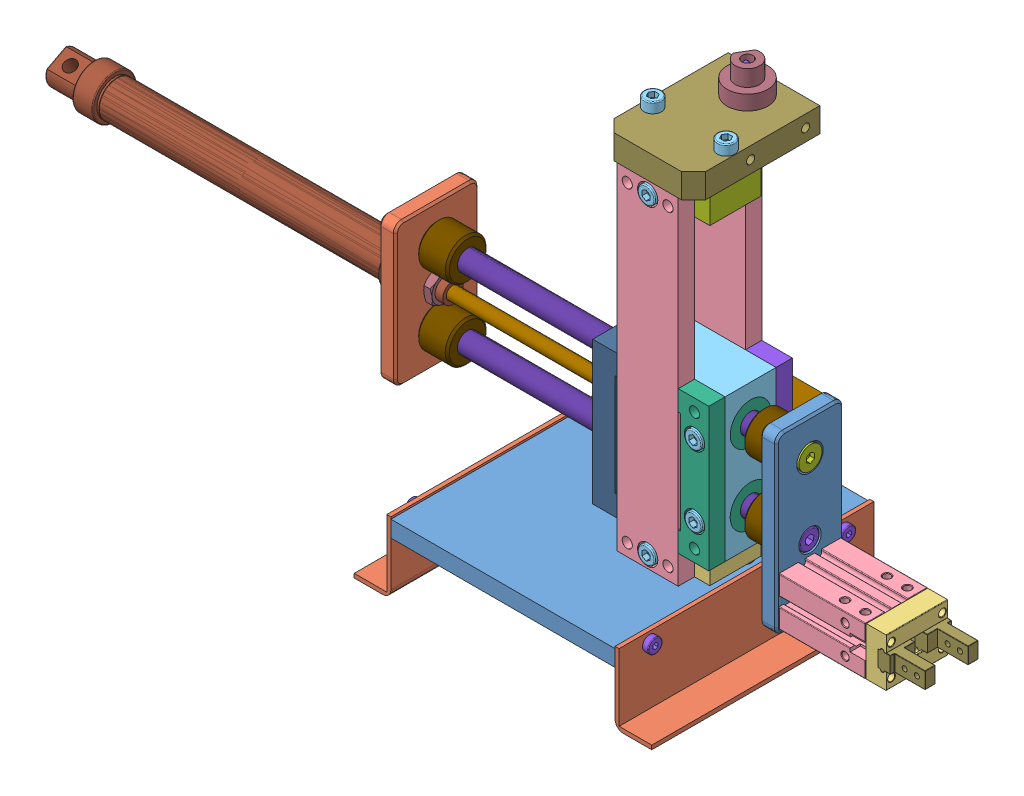
SolidWorks assembly Cum_lap_rap_S5_hoan_thien, configuration Default. Lengths in mm.
Overall size (436.7 226.2 125).
64 component instances, 31 part files, 157 mates.
Components (placement in the parent):
- tam de lon-1: tam de lon [Default] at (42.5889 56.6685 101.1963) size (110 8 125)
- khoi do-1: khoi do [Default] at (98.4472 49.4552 163.6963) x (0 0 -1) z (-1 0 0) size (125 35 18)
- khoi do-2: khoi do [Default] at (-13.2695 49.4552 38.6963) x (0 0 1) z (1 0 0) size (125 35 18)
- mieng dem duoi-1: mieng dem duoi [Default] at (71.5889 64.6685 101.1963) size (45 12 25)
- thanh dan huong lon x2-1: thanh dan huong lon x2 [Default] at (71.5889 147.1685 113.6963) x (1 0 0) z (0 -1 0) size (30 8 165)
- thanh dan huong lon x2-2: thanh dan huong lon x2 [Default] at (71.5889 147.1685 88.6963) x (1 0 0) z (0 1 0) size (30 8 165)
- con truot s4 -1: con truot s4  [Default] at (79.0889 78.6685 101.1963) x (-1 0 0) z (0 0 -1) size (45 70 25)
- bac lot-1: bac lot [Default] at (101.5889 96.1685 101.1963) x (0 1 0) z (0 0 1) size (20 12 20)
- bac lot-2: bac lot [Default] at (101.5889 131.1685 101.1963) x (0 1 0) z (0 0 1) size (20 12 20)
- bac lot-3: bac lot [Default] at (56.5889 131.1685 101.1963) x (0 0.381849 -0.924225) z (0 -0.924225 -0.381849) size (20 12 20)
- bac lot-4: bac lot [Default] at (56.5889 96.1685 101.1963) x (0 0.381849 -0.924225) z (0 -0.924225 -0.381849) size (20 12 20)
- mieng dem tren-1: mieng dem tren [Default] at (71.5889 217.6685 101.1963) size (45 12 25)
- thanh dan huong so 2 s4-3: thanh dan huong so 2 s4 [Default] at (94.0889 113.6685 88.6963) x (-1 0 0) z (0 -1 0) size (15 8 70)
- thanh ngang-5: thanh ngang [Default] at (73.0889 110.6685 65.6963) x (-1 0 0) z (0 1 0) size (57 15 25)
- tam dan huong-4: tam dan huong [Default] at (44.5889 113.6685 101.1963) x (0 -1 0) z (0 0 1) size (70 12 41)
- dai oc-1: dai oc [Default] at (71.5889 113.6685 65.6963) x (0 1 0) z (1 0 0) size (16 14 16)
- tam de nho-4: tam de nho [Default] at (71.5889 241.6685 90.6963) x (1 0 0) z (0 0 -1) size (45 12 62)
- dau kep truc vit-2: dau kep truc vit [Default] at (71.5889 256.8685 72.6963) x (-0.859142 0 -0.511737) z (-0.511737 0 0.859142) size (20 25 20)
- vong_dem-2: vong_dem [Default] at (71.5889 229.8685 72.6963) x (0.969315 0 0.245821) z (-0.245821 0 0.969315) size (19.6 2 19.6)
- vit me M8x150mm-2: vit me M8x150mm [Default] at (71.5889 171.8685 72.6963) x (0.924585 0 -0.380975) z (0 1 0) size (10.85 10.06 150.11)
- hex nut gradec_din-2: hex nut gradec_din [Hexagon Nut ISO 4034 - M8 - N] at (71.5889 221.9685 72.6963) x (-0.859606 0 0.510958) z (0 -1 0) size (13 15.01 7.9)
- chot dan huong-1: chot dan huong [Default] at (122.7513 131.1685 101.1963) x (0 0.988897 -0.148604) z (0 0.148604 0.988897) size (10 175 10)
- chot dan huong-2: chot dan huong [Default] at (122.7513 96.1685 101.1963) x (0 0.324021 0.94605) z (0 -0.94605 0.324021) size (10 175 10)
- bac chan-1: bac chan [Default] at (122.7513 131.1685 101.1963) x (0 0.942027 0.335537) z (0 -0.335537 0.942027) size (20 15 20)
- bac chan-2: bac chan [Default] at (122.7513 96.1685 101.1963) x (0 1 0) z (0 0 1) size (20 15 20)
- bac chan-3: bac chan [Default] at (-37.2487 131.1685 101.1963) x (0 0.628565 -0.777757) z (0 0.777757 0.628565) size (20 15 20)
- bac chan-4: bac chan [Default] at (-37.2487 96.1685 101.1963) x (0 0.99939 -0.03491) z (0 0.03491 0.99939) size (20 15 20)
- ban canh truoc-1: ban canh truoc [Default] at (122.7513 105.6685 101.1963) x (0 0 -1) z (0 -1 0) size (33 8 86)
- ban canh sau-1: ban canh sau [Default] at (-52.2487 113.6685 101.1963) x (0 0 -1) z (0 1 0) size (41 8 70)
- NMHZ2-16D-2: NMHZ2-16D [Default] at (115.7633 75.1106 123.6032) x (0 0 -1) z (1 0 0) size (30.6 23.6 52.5)
  - NMHZ2-16D Slipway-1: NMHZ2-16D Slipway [Default] at (22.4069 2.6078 57.488) size (30.1 23.6 10)
  - NMHZ2-16D cylinder-2: NMHZ2-16D cylinder [Default] at (22.4069 2.6078 14.988) size (30.6 23.6 42.5)
- socket head cap screw_din-2: socket head cap screw_din [DIN 912 M5 x 16 --- 16N] at (94.5889 131.1685 79.8963) x (0 0 1) z (-1 0 0) size (21 8.5 8.5)
- socket head cap screw_din-3: socket head cap screw_din [DIN 912 M5 x 16 --- 16N] at (50.0889 107.1685 66.3963) x (0 0 1) z (-1 0 0) size (21 8.5 8.5)
- socket head cap screw_din-4: socket head cap screw_din [DIN 912 M5 x 16 --- 16N] at (94.5889 120.1685 66.3963) x (0 0 1) z (-1 0 0) size (21 8.5 8.5)
- socket head cap screw_din-5: socket head cap screw_din [DIN 912 M5 x 16 --- 16N] at (94.5889 96.1685 79.8963) x (0 0 1) z (-1 0 0) size (21 8.5 8.5)
- socket head cap screw_din-6: socket head cap screw_din [DIN 912 M5 x 16 --- 16N] at (71.5889 70.6685 79.8963) x (0 0 1) z (0.989815 0.142357 0) size (21 8.5 8.5)
- socket head cap screw_din-9: socket head cap screw_din [DIN 912 M5 x 8 --- 8N] at (71.5889 70.6685 122.4963) x (0 0 -1) z (1 0 0) size (13 8.5 8.5)
- socket head cap screw_din-10: socket head cap screw_din [DIN 912 M5 x 8 --- 8N] at (45.2889 84.6685 108.6963) size (13 8.5 8.5)
- socket head cap screw_din-11: socket head cap screw_din [DIN 912 M5 x 8 --- 8N] at (45.2889 142.6685 93.6963) size (13 8.5 8.5)
- thanh dan huong s4-1: thanh dan huong s4 [Default] at (94.0889 113.6685 113.6963) x (-1 0 0) z (0 1 0) size (15 8 70)
- socket head cap screw_din-13: socket head cap screw_din [DIN 912 M5 x 12 --- 12N] at (94.5889 96.1685 122.4963) x (0 0 -1) z (1 0 0) size (17 8.5 8.5)
- socket head cap screw_din-14: socket head cap screw_din [DIN 912 M5 x 12 --- 12N] at (94.5889 131.1685 122.4963) x (0 0 -1) z (1 0 0) size (17 8.5 8.5)
- socket head cap screw_din-15: socket head cap screw_din [DIN 912 M5 x 12 --- 12N] at (53.5889 246.6685 101.1963) x (0 -1 0) z (0 0 1) size (17 8.5 8.5)
- socket head cap screw_din-16: socket head cap screw_din [DIN 912 M5 x 12 --- 12N] at (89.5889 246.6685 101.1963) x (0 -1 0) z (0 0 1) size (17 8.5 8.5)
- socket head cap screw_din-17: socket head cap screw_din [DIN 912 M5 x 12 --- 12N] at (71.5889 223.6685 79.8963) x (0 0 1) z (-1 0 0) size (17 8.5 8.5)
- socket head cap screw_din-18: socket head cap screw_din [DIN 912 M5 x 12 --- 12N] at (71.5889 223.6685 122.4963) x (0 0 -1) z (1 0 0) size (17 8.5 8.5)
- socket csink head cap screw 10642_din-2: socket csink head cap screw 10642_din [EN ISO 10642 - M6 x 8 - 8N] at (-60.4687 131.1685 101.1963) x (1 0 0) z (0 0.02259 0.999745) size (8 11.34 11.34)
- socket csink head cap screw 10642_din-3: socket csink head cap screw 10642_din [EN ISO 10642 - M6 x 8 - 8N] at (130.9713 131.1685 101.1963) x (-1 0 0) z (0 -0.022602 -0.999745) size (8 11.34 11.34)
- socket head thin cap screw_din-2: socket head thin cap screw_din [DIN 7984 - M6 x 10 --- 7N] at (130.5513 96.1685 101.1963) x (-1 0 0) z (0 0.924225 0.381849) size (14 10 10)
- socket head thin cap screw_din-4: socket head thin cap screw_din [DIN 7984 - M6 x 10 --- 7N] at (-60.0487 96.1685 101.1963) size (14 10 10)
- socket head thin cap screw_din-5: socket head thin cap screw_din [DIN 7984 - M4 x 6 --- 3.9N] at (-17.2111 60.6685 53.6963) size (8.8 7 7)
- socket head thin cap screw_din-6: socket head thin cap screw_din [DIN 7984 - M4 x 6 --- 3.9N] at (-17.2111 60.6685 148.6963) size (8.8 7 7)
- socket head thin cap screw_din-7: socket head thin cap screw_din [DIN 7984 - M4 x 6 --- 3.9N] at (102.3889 60.6685 53.6963) x (-1 0 0) z (0 0.924225 0.381849) size (8.8 7 7)
- socket head thin cap screw_din-8: socket head thin cap screw_din [DIN 7984 - M4 x 6 --- 3.9N] at (102.3889 60.6685 148.6963) x (-1 0 0) z (0 0.924225 0.381849) size (8.8 7 7)
- socket head thin cap screw_din-10: socket head thin cap screw_din [DIN 7984 - M4 x 12 --- 9.9N] at (124.3513 70.3685 112.1963) size (14.8 7 7)
- socket head thin cap screw_din-11: socket head thin cap screw_din [DIN 7984 - M4 x 12 --- 9.9N] at (124.3513 85.3685 90.1963) size (14.8 7 7)
- socket head thin cap screw_din-18: socket head thin cap screw_din [DIN 7984 - M3 x 5 --- 3.5N] at (66.0045 252.8685 69.37) x (0.859142 0 0.511737) z (0.205408 0.915906 -0.344854) size (7 5.5 5.5)
- Rod-1: Rod [Default] at (-92.4392 113.6685 101.1963) x (0 0.871767 -0.48992) z (0 -0.48992 -0.871767) size (6.2 165 6.2)
- Nut 5-1: Nut 5 [Default] at (55.0889 113.6685 101.1963) x (0 0.12782 0.991797) z (0 0.991797 -0.12782) size (11.32 3 9.8)
- 16 X 100 Cylinder bore-2: 16 X 100 Cylinder bore [Default] at (-140.4487 113.6685 101.1963) x (0 -0.886193 -0.463316) z (-1 0 0) size (21.5 21.5 192)
- NMHZ2-16D air claw-1: NMHZ2-16D air claw [Default] at (181.2513 77.7185 98.1463) x (0 0 -1) z (1 0 0) size (12 10 21)
- NMHZ2-16D air claw-2: NMHZ2-16D air claw [Default] at (181.2513 77.7185 104.2463) x (0 0 1) z (1 0 0) size (12 10 21)
- hex thin nut chamfered gradeab_din-1: hex thin nut chamfered gradeab_din [Hexagon Thin Nut ISO 4035 - M8 - N] at (-52.2487 113.6685 101.1963) x (0 -0.129819 0.991538) z (-1 0 0) size (13 15.01 4)
Mates (geometry in assembly coordinates):
- Parallel1: parallel anti-aligned: plane of tam de lon-1 through (42.5889 64.6685 101.1963) normal (0 1 0); plane of khoi do-1 through (97.5889 30.6685 38.6963) normal (0 -1 0)
- Parallel2: parallel anti-aligned: plane of tam de lon-1 through (97.5889 64.6685 38.6963) normal (1 0 0); plane of khoi do-1 through (97.5889 30.6685 38.6963) normal (-1 0 0)
- Concentric1: concentric aligned: cylinder of tam de lon-1 through (82.5889 60.6685 53.6963) axis (1 0 0) radius 2.5; cylinder of khoi do-1 through (-25.4111 60.6685 53.6963) axis (1 0 0) radius 2.5
- Coincident1: coincident anti-aligned: plane of tam de lon-1 through (97.5889 64.6685 38.6963) normal (1 0 0); plane of khoi do-1 through (97.5889 30.6685 38.6963) normal (-1 0 0)
- Parallel3: parallel anti-aligned: plane of tam de lon-1 through (42.5889 64.6685 101.1963) normal (0 1 0); plane of khoi do-2 through (-12.4111 30.6685 163.6963) normal (0 -1 0)
- Parallel4: parallel anti-aligned: plane of tam de lon-1 through (-12.4111 64.6685 38.6963) normal (-1 0 0); plane of khoi do-2 through (-12.4111 30.6685 163.6963) normal (1 0 0)
- Concentric2: concentric aligned: cylinder of tam de lon-1 through (2.5889 60.6685 148.6963) axis (-1 0 0) radius 2.5; cylinder of khoi do-2 through (110.5889 60.6685 148.6963) axis (-1 0 0) radius 2.5
- Coincident2: coincident anti-aligned: plane of tam de lon-1 through (-12.4111 64.6685 38.6963) normal (-1 0 0); plane of khoi do-2 through (-12.4111 30.6685 163.6963) normal (1 0 0)
- Concentric3: concentric aligned: cylinder of tam de lon-1 through (89.5889 56.6685 93.6963) axis (0 1 0) radius 2.75; cylinder of mieng dem duoi-1 through (89.5889 64.6685 93.6963) axis (0 1 0) radius 2.5
- Concentric4: concentric aligned: cylinder of tam de lon-1 through (53.5889 56.6685 108.6963) axis (0 1 0) radius 2.75; cylinder of mieng dem duoi-1 through (53.5889 64.6685 108.6963) axis (0 1 0) radius 2.5
- Coincident3: coincident anti-aligned: plane of tam de lon-1 through (42.5889 64.6685 101.1963) normal (0 1 0); plane of mieng dem duoi-1 through (71.5889 64.6685 101.1963) normal (0 -1 0)
- Parallel6: parallel anti-aligned: plane of mieng dem duoi-1 through (71.5889 76.6685 101.1963) normal (0 1 0); plane of thanh dan huong lon x2-1 through (56.5889 64.6685 121.6963) normal (0 -1 0)
- Parallel7: parallel anti-aligned: plane of mieng dem duoi-1 through (49.0889 76.6685 113.6963) normal (0 0 1); plane of thanh dan huong lon x2-1 through (71.5889 147.1685 113.6963) normal (0 0 -1)
- Concentric5: concentric anti-aligned: cylinder of mieng dem duoi-1 through (81.5889 70.6685 160.6963) axis (0 0 -1) radius 2.5; cylinder of thanh dan huong lon x2-1 through (81.5889 70.6685 80.4963) axis (0 0 1) radius 2.5
- Coincident4: coincident anti-aligned: plane of mieng dem duoi-1 through (49.0889 76.6685 113.6963) normal (0 0 1); plane of thanh dan huong lon x2-1 through (71.5889 147.1685 113.6963) normal (0 0 -1)
- Parallel8: parallel anti-aligned: plane of mieng dem duoi-1 through (71.5889 76.6685 101.1963) normal (0 1 0); plane of thanh dan huong lon x2-2 through (56.5889 64.6685 80.6963) normal (0 -1 0)
- Parallel9: parallel anti-aligned: plane of mieng dem duoi-1 through (49.0889 76.6685 88.6963) normal (0 0 -1); plane of thanh dan huong lon x2-2 through (71.5889 147.1685 88.6963) normal (0 0 1)
- Concentric6: concentric aligned: cylinder of mieng dem duoi-1 through (81.5889 70.6685 160.6963) axis (0 0 -1) radius 2.5; cylinder of thanh dan huong lon x2-2 through (81.5889 70.6685 121.8963) axis (0 0 -1) radius 2.5
- Coincident5: coincident anti-aligned: plane of mieng dem duoi-1 through (49.0889 76.6685 88.6963) normal (0 0 -1); plane of thanh dan huong lon x2-2 through (71.5889 147.1685 88.6963) normal (0 0 1)
- Parallel10: parallel anti-aligned: plane of mieng dem duoi-1 through (94.0889 76.6685 88.6963) normal (1 0 0); plane of con truot s4 -1 through (56.5889 148.6685 113.6963) normal (-1 0 0)
- Parallel11: parallel aligned: plane of mieng dem duoi-1 through (71.5889 76.6685 101.1963) normal (0 1 0); plane of con truot s4 -1 through (79.0889 148.6685 101.1963) normal (0 1 0)
- Coincident6: coincident anti-aligned: plane of thanh dan huong lon x2-2 through (71.5889 147.1685 88.6963) normal (0 0 1); plane of con truot s4 -1 through (101.5889 148.6685 88.6963) normal (0 0 -1)
- Concentric7: concentric anti-aligned: cylinder of con truot s4 -1 through (126.5889 96.1685 101.1963) axis (-1 0 0) radius 6; cylinder of bac lot-1 through (89.5889 96.1685 101.1963) axis (1 0 0) radius 6
- Coincident14: coincident anti-aligned: plane of con truot s4 -1 through (99.5889 96.1685 101.1963) normal (1 0 0); plane of bac lot-1 through (99.5889 96.1685 101.1963) normal (-1 0 0)
- Concentric8: concentric anti-aligned: cylinder of con truot s4 -1 through (126.5889 131.1685 101.1963) axis (-1 0 0) radius 6; cylinder of bac lot-2 through (89.5889 131.1685 101.1963) axis (1 0 0) radius 6
- Coincident15: coincident anti-aligned: plane of con truot s4 -1 through (99.5889 131.1685 101.1963) normal (1 0 0); plane of bac lot-2 through (99.5889 131.1685 101.1963) normal (-1 0 0)
- Concentric9: concentric aligned: cylinder of con truot s4 -1 through (126.5889 131.1685 101.1963) axis (-1 0 0) radius 6; cylinder of bac lot-3 through (68.5889 131.1685 101.1963) axis (-1 0 0) radius 6
- Coincident16: coincident anti-aligned: plane of con truot s4 -1 through (58.5889 131.1685 101.1963) normal (-1 0 0); plane of bac lot-3 through (58.5889 131.1685 101.1963) normal (1 0 0)
- Concentric10: concentric aligned: cylinder of con truot s4 -1 through (126.5889 96.1685 101.1963) axis (-1 0 0) radius 6; cylinder of bac lot-4 through (68.5889 96.1685 101.1963) axis (-1 0 0) radius 6
- Coincident18: coincident anti-aligned: plane of con truot s4 -1 through (58.5889 96.1685 101.1963) normal (-1 0 0); plane of bac lot-4 through (58.5889 96.1685 101.1963) normal (1 0 0)
- Parallel23: parallel aligned: plane of thanh dan huong lon x2-2 through (56.5889 229.6685 80.6963) normal (0 1 0); plane of mieng dem tren-1 through (71.5889 229.6685 101.1963) normal (0 1 0)
- Concentric12: concentric aligned: cylinder of thanh dan huong lon x2-2 through (61.5889 223.6685 121.8963) axis (0 0 -1) radius 2.5; cylinder of mieng dem tren-1 through (61.5889 223.6685 160.6963) axis (0 0 -1) radius 2.5
- Coincident21: coincident anti-aligned: plane of thanh dan huong lon x2-2 through (71.5889 147.1685 88.6963) normal (0 0 1); plane of mieng dem tren-1 through (49.0889 229.6685 88.6963) normal (0 0 -1)
- Parallel38: parallel aligned: plane of con truot s4 -1 through (79.0889 148.6685 101.1963) normal (0 1 0); plane of thanh dan huong so 2 s4-3 through (101.5889 148.6685 80.6963) normal (0 1 0)
- Parallel39: parallel anti-aligned: plane of con truot s4 -1 through (101.5889 148.6685 88.6963) normal (0 0 -1); plane of thanh dan huong so 2 s4-3 through (94.0889 113.6685 88.6963) normal (0 0 1)
- Coincident32: coincident aligned: plane of con truot s4 -1 through (79.0889 148.6685 101.1963) normal (0 1 0); plane of thanh dan huong so 2 s4-3 through (101.5889 148.6685 80.6963) normal (0 1 0)
- Coincident33: coincident aligned: plane of con truot s4 -1 through (101.5889 148.6685 113.6963) normal (1 0 0); plane of thanh dan huong so 2 s4-3 through (101.5889 148.6685 80.6963) normal (1 0 0)
- Coincident34: coincident anti-aligned: plane of con truot s4 -1 through (101.5889 148.6685 88.6963) normal (0 0 -1); plane of thanh dan huong so 2 s4-3 through (94.0889 113.6685 88.6963) normal (0 0 1)
- Coincident36: coincident anti-aligned: plane of thanh dan huong lon x2-2 through (86.5889 64.6685 80.6963) normal (1 0 0); plane of thanh dan huong so 2 s4-3 through (86.5889 148.6685 80.6963) normal (-1 0 0)
- Parallel42: parallel anti-aligned: plane of thanh dan huong so 2 s4-3 through (101.5889 148.6685 80.6963) normal (0 1 0); plane of thanh ngang-5 through (101.5889 101.1685 80.6963) normal (0 -1 0)
- Concentric26: concentric aligned: cylinder of thanh dan huong so 2 s4-3 through (94.5889 120.1685 152.8963) axis (0 0 -1) radius 2.5; cylinder of thanh ngang-5 through (94.5889 120.1685 124.3963) axis (0 0 -1) radius 2.75
- Parallel46: parallel aligned: plane of con truot s4 -1 through (79.0889 148.6685 101.1963) normal (0 1 0); plane of tam dan huong-4 through (56.5889 148.6685 80.6963) normal (0 1 0)
- Parallel47: parallel anti-aligned: plane of con truot s4 -1 through (56.5889 148.6685 113.6963) normal (-1 0 0); plane of tam dan huong-4 through (55.5889 138.6685 33.6963) normal (1 0 0)
- Coincident40: coincident anti-aligned: plane of con truot s4 -1 through (56.5889 148.6685 113.6963) normal (-1 0 0); plane of tam dan huong-4 through (56.5889 113.6685 101.1963) normal (1 0 0)
- Concentric29: concentric aligned: cylinder of con truot s4 -1 through (71.5889 142.6685 93.6963) axis (-1 0 0) radius 2.5; cylinder of tam dan huong-4 through (132.5889 142.6685 93.6963) axis (-1 0 0) radius 2.75
- Coincident41: coincident anti-aligned: plane of thanh dan huong so 2 s4-3 through (94.0889 113.6685 80.6963) normal (0 0 -1); plane of thanh ngang-5 through (73.0889 110.6685 80.6963) normal (0 0 1)
- Parallel48: parallel anti-aligned: plane of thanh ngang-5 through (73.0889 110.6685 65.6963) normal (0 0 -1); plane of dai oc-1 through (80.1238 134.6685 79.6963) normal (0 0 1)
- Concentric30: concentric anti-aligned: cylinder of thanh ngang-5 through (71.5889 -44.8315 72.6963) axis (0 1 0) radius 5; cylinder of dai oc-1 through (71.5889 134.6685 72.6963) axis (0 -1 0) radius 4
- Concentric31: concentric aligned: cylinder of thanh ngang-5 through (71.5889 113.6685 236.6963) axis (0 0 -1) radius 8; cylinder of dai oc-1 through (71.5889 113.6685 79.6963) axis (0 0 -1) radius 8
- Parallel53: parallel anti-aligned: plane of mieng dem tren-1 through (71.5889 229.6685 101.1963) normal (0 1 0); plane of tam de nho-4 through (71.5889 229.6685 90.6963) normal (0 -1 0)
- Parallel54: parallel anti-aligned: plane of mieng dem tren-1 through (94.0889 229.6685 88.6963) normal (1 0 0); plane of tam de nho-4 through (49.0889 229.6685 121.6963) normal (-1 0 0)
- Concentric32: concentric anti-aligned: cylinder of mieng dem tren-1 through (53.5889 157.6685 101.1963) axis (0 1 0) radius 2.5; cylinder of tam de nho-4 through (53.5889 241.6685 101.1963) axis (0 -1 0) radius 2.75
- Coincident45: coincident anti-aligned: plane of mieng dem tren-1 through (71.5889 229.6685 101.1963) normal (0 1 0); plane of tam de nho-4 through (71.5889 229.6685 90.6963) normal (0 -1 0)
- Parallel55: parallel anti-aligned: plane of tam de nho-4 through (71.5889 241.6685 90.6963) normal (0 1 0); plane of dau kep truc vit-2 through (71.5889 231.8685 72.6963) normal (0 -1 0)
- Concentric33: concentric aligned: cylinder of tam de nho-4 through (71.5889 241.6685 72.6963) axis (0 -1 0) radius 7; cylinder of dau kep truc vit-2 through (71.5889 241.6685 72.6963) axis (0 -1 0) radius 7
- Coincident46: coincident anti-aligned: plane of tam de nho-4 through (71.5889 241.6685 90.6963) normal (0 1 0); plane of dau kep truc vit-2 through (71.5889 241.6685 72.6963) normal (0 -1 0)
- Concentric34: concentric aligned: cylinder of dau kep truc vit-2 through (71.5889 246.8685 72.6963) axis (0 -1 0) radius 4; cylinder of vong_dem-2 through (71.5889 231.8685 72.6963) axis (0 -1 0) radius 4.25
- Coincident47: coincident anti-aligned: plane of dau kep truc vit-2 through (71.5889 231.8685 72.6963) normal (0 -1 0); plane of vong_dem-2 through (71.5889 231.8685 72.6963) normal (0 1 0)
- Concentric35: concentric anti-aligned: cylinder of dau kep truc vit-2 through (71.5889 246.8685 72.6963) axis (0 -1 0) radius 4; cylinder of vit me M8x150mm-2 through (71.5889 171.8685 72.6963) axis (0 1 0) radius 3.933
- Coincident48: coincident anti-aligned: plane of dau kep truc vit-2 through (71.5889 246.8685 72.6963) normal (0 -1 0); plane of vit me M8x150mm-2 through (71.5889 246.8685 72.6963) normal (0 1 0)
- Concentric37: concentric anti-aligned: cylinder of vit me M8x150mm-2 through (71.5889 171.8685 72.6963) axis (0 1 0) radius 3.933; cylinder of hex nut gradec_din-2 through (71.5889 229.8685 72.6963) axis (0 -1 0) radius 3.4
- Coincident49: coincident anti-aligned: plane of vong_dem-2 through (71.5889 229.8685 72.6963) normal (0 -1 0); plane of hex nut gradec_din-2 through (67.7539 229.8685 66.2445) normal (0 1 0)
- Lock1: lock: unknown of vit me M8x150mm-2; unknown of hex nut gradec_din-2
- Lock2: lock: unknown of dau kep truc vit-2; unknown of hex nut gradec_din-2
- Concentric41: concentric anti-aligned: cylinder of bac lot-2 through (116.5889 131.1685 101.1963) axis (-1 0 0) radius 5; cylinder of chot dan huong-1 through (-150.2487 131.1685 101.1963) axis (1 0 0) radius 5
- Concentric42: concentric anti-aligned: cylinder of bac lot-1 through (116.5889 96.1685 101.1963) axis (-1 0 0) radius 5; cylinder of chot dan huong-2 through (-150.2487 96.1685 101.1963) axis (1 0 0) radius 5
- Concentric43: concentric anti-aligned: cylinder of chot dan huong-1 through (-150.2487 131.1685 101.1963) axis (1 0 0) radius 5; cylinder of bac chan-1 through (122.7513 131.1685 101.1963) axis (-1 0 0) radius 5
- Coincident53: coincident aligned: plane of chot dan huong-1 through (122.7513 131.1685 101.1963) normal (1 0 0); plane of bac chan-1 through (122.7513 131.1685 101.1963) normal (1 0 0)
- Concentric44: concentric anti-aligned: cylinder of chot dan huong-2 through (-150.2487 96.1685 101.1963) axis (1 0 0) radius 5; cylinder of bac chan-2 through (122.7513 96.1685 101.1963) axis (-1 0 0) radius 5
- Coincident54: coincident aligned: plane of chot dan huong-2 through (122.7513 96.1685 101.1963) normal (1 0 0); plane of bac chan-2 through (122.7513 96.1685 101.1963) normal (1 0 0)
- Concentric45: concentric anti-aligned: cylinder of chot dan huong-1 through (-150.2487 131.1685 101.1963) axis (1 0 0) radius 5; cylinder of bac chan-3 through (-37.2487 131.1685 101.1963) axis (-1 0 0) radius 5
- Coincident55: coincident aligned: plane of chot dan huong-1 through (-52.2487 131.1685 101.1963) normal (-1 0 0); plane of bac chan-3 through (-52.2487 131.1685 101.1963) normal (-1 0 0)
- Coincident57: coincident aligned: plane of chot dan huong-2 through (-52.2487 96.1685 101.1963) normal (-1 0 0); plane of bac chan-4 through (-52.2487 96.1685 101.1963) normal (-1 0 0)
- Concentric47: concentric aligned: cylinder of chot dan huong-1 through (102.7513 131.1685 101.1963) axis (1 0 0) radius 3; cylinder of ban canh truoc-1 through (122.7513 131.1685 101.1963) axis (1 0 0) radius 3.3
- Concentric48: concentric aligned: cylinder of chot dan huong-2 through (102.7513 96.1685 101.1963) axis (1 0 0) radius 3; cylinder of ban canh truoc-1 through (122.7513 96.1685 101.1963) axis (1 0 0) radius 3.3
- Coincident58: coincident anti-aligned: plane of chot dan huong-1 through (122.7513 131.1685 101.1963) normal (1 0 0); plane of ban canh truoc-1 through (122.7513 105.6685 101.1963) normal (-1 0 0)
- Coincident59: coincident anti-aligned: plane of chot dan huong-2 through (122.7513 96.1685 101.1963) normal (1 0 0); plane of ban canh truoc-1 through (122.7513 105.6685 101.1963) normal (-1 0 0)
- Concentric49: concentric aligned: cylinder of chot dan huong-1 through (-32.2487 131.1685 101.1963) axis (-1 0 0) radius 3; cylinder of ban canh sau-1 through (-52.2487 131.1685 101.1963) axis (-1 0 0) radius 3.3
- Concentric50: concentric aligned: cylinder of chot dan huong-2 through (-32.2487 96.1685 101.1963) axis (-1 0 0) radius 3; cylinder of ban canh sau-1 through (-52.2487 96.1685 101.1963) axis (-1 0 0) radius 3.3
- Coincident60: coincident anti-aligned: plane of chot dan huong-1 through (-52.2487 131.1685 101.1963) normal (-1 0 0); plane of ban canh sau-1 through (-52.2487 113.6685 101.1963) normal (1 0 0)
- Coincident61: coincident anti-aligned: plane of chot dan huong-2 through (-52.2487 96.1685 101.1963) normal (-1 0 0); plane of ban canh sau-1 through (-52.2487 113.6685 101.1963) normal (1 0 0)
- Concentric55: concentric anti-aligned: cylinder of ban canh truoc-1 through (122.7513 70.3685 112.1963) axis (1 0 0) radius 2.25; cylinder of NMHZ2-16D-2/NMHZ2-16D cylinder-2 through (145.7513 70.3685 112.1963) axis (-1 0 0) radius 2
- Concentric56: concentric anti-aligned: cylinder of ban canh truoc-1 through (122.7513 85.3685 90.1963) axis (1 0 0) radius 2.25; cylinder of NMHZ2-16D-2/NMHZ2-16D cylinder-2 through (145.7513 85.3685 90.1963) axis (-1 0 0) radius 2
- Coincident62: coincident anti-aligned: plane of ban canh truoc-1 through (130.7513 105.6685 101.1963) normal (1 0 0); plane of NMHZ2-16D-2/NMHZ2-16D cylinder-2 through (130.7513 77.7185 101.1963) normal (-1 0 0)
- Concentric57: concentric anti-aligned: cylinder of chot dan huong-2 through (-150.2487 96.1685 101.1963) axis (1 0 0) radius 5; cylinder of bac chan-4 through (-37.2487 96.1685 101.1963) axis (-1 0 0) radius 5
- Concentric61: concentric aligned: cylinder of thanh dan huong so 2 s4-3 through (94.5889 131.1685 88.6963) axis (0 0 -1) radius 2.75; cylinder of socket head cap screw_din-2 through (94.5889 131.1685 48.1463) axis (0 0 -1) radius 4.25
- Coincident66: coincident anti-aligned: plane of thanh dan huong so 2 s4-3 through (94.5889 131.1685 84.8963) normal (0 0 -1); plane of socket head cap screw_din-2 through (94.5889 135.4185 84.8963) normal (0 0 1)
- Concentric62: concentric aligned: cylinder of thanh ngang-5 through (50.0889 107.1685 71.3963) axis (0 0 -1) radius 5; cylinder of socket head cap screw_din-3 through (50.0889 107.1685 34.6463) axis (0 0 -1) radius 4.25
- Coincident67: coincident anti-aligned: plane of thanh ngang-5 through (50.0889 107.1685 71.3963) normal (0 0 -1); plane of socket head cap screw_din-3 through (50.0889 111.4185 71.3963) normal (0 0 1)
- Concentric63: concentric aligned: cylinder of thanh ngang-5 through (94.5889 120.1685 124.3963) axis (0 0 -1) radius 2.75; cylinder of socket head cap screw_din-4 through (94.5889 120.1685 34.6463) axis (0 0 -1) radius 4.25
- Coincident68: coincident anti-aligned: plane of thanh ngang-5 through (94.5889 120.1685 71.3963) normal (0 0 -1); plane of socket head cap screw_din-4 through (94.5889 124.4185 71.3963) normal (0 0 1)
- Concentric64: concentric aligned: cylinder of thanh dan huong so 2 s4-3 through (94.5889 96.1685 88.6963) axis (0 0 -1) radius 2.75; cylinder of socket head cap screw_din-5 through (94.5889 96.1685 48.1463) axis (0 0 -1) radius 4.25
- Coincident69: coincident anti-aligned: plane of thanh dan huong so 2 s4-3 through (94.5889 96.1685 84.8963) normal (0 0 -1); plane of socket head cap screw_din-5 through (94.5889 100.4185 84.8963) normal (0 0 1)
- Concentric651: concentric aligned: cylinder of thanh dan huong lon x2-2 through (71.5889 70.6685 88.6963) axis (0 0 -1) radius 2.75; cylinder of socket head cap screw_din-6 through (71.5889 70.6685 48.1463) axis (0 0 -1) radius 4.25
- Coincident701: coincident anti-aligned: plane of thanh dan huong lon x2-2 through (71.5889 70.6685 84.8963) normal (0 0 -1); plane of socket head cap screw_din-6 through (72.1939 66.4617 84.8963) normal (0 0 1)
- Concentric66: concentric aligned: cylinder of thanh dan huong lon x2-1 through (71.5889 70.6685 113.6963) axis (0 0 1) radius 2.75; cylinder of socket head cap screw_din-9 through (71.5889 70.6685 154.2463) axis (0 0 1) radius 4.25
- Coincident71: coincident anti-aligned: plane of thanh dan huong lon x2-1 through (71.5889 70.6685 117.4963) normal (0 0 1); plane of socket head cap screw_din-9 through (71.5889 74.9185 117.4963) normal (0 0 -1)
- Concentric67: concentric aligned: cylinder of tam dan huong-4 through (132.5889 84.6685 108.6963) axis (-1 0 0) radius 2.75; cylinder of socket head cap screw_din-10 through (13.5389 84.6685 108.6963) axis (-1 0 0) radius 4.25
- Coincident72: coincident anti-aligned: plane of tam dan huong-4 through (50.2889 84.6685 108.6963) normal (-1 0 0); plane of socket head cap screw_din-10 through (50.2889 88.9185 108.6963) normal (1 0 0)
- Concentric68: concentric aligned: cylinder of tam dan huong-4 through (132.5889 142.6685 93.6963) axis (-1 0 0) radius 2.75; cylinder of socket head cap screw_din-11 through (13.5389 142.6685 93.6963) axis (-1 0 0) radius 4.25
- Coincident73: coincident anti-aligned: plane of tam dan huong-4 through (50.2889 142.6685 93.6963) normal (-1 0 0); plane of socket head cap screw_din-11 through (50.2889 146.9185 93.6963) normal (1 0 0)
- Parallel62: parallel aligned: plane of con truot s4 -1 through (101.5889 148.6685 113.6963) normal (0 0 1); plane of thanh dan huong s4-1 through (94.0889 113.6685 121.6963) normal (0 0 1)
- Parallel63: parallel aligned: plane of con truot s4 -1 through (101.5889 148.6685 113.6963) normal (1 0 0); plane of thanh dan huong s4-1 through (101.5889 78.6685 121.6963) normal (1 0 0)
- Concentric71: concentric anti-aligned: cylinder of con truot s4 -1 through (94.5889 96.1685 124.6963) axis (0 0 -1) radius 2.5; cylinder of thanh dan huong s4-1 through (94.5889 96.1685 113.6963) axis (0 0 1) radius 2.75
- Coincident76: coincident anti-aligned: plane of con truot s4 -1 through (101.5889 148.6685 113.6963) normal (0 0 1); plane of thanh dan huong s4-1 through (94.0889 113.6685 113.6963) normal (0 0 -1)
- Concentric72: concentric aligned: cylinder of thanh dan huong s4-1 through (94.5889 96.1685 113.6963) axis (0 0 1) radius 2.75; cylinder of socket head cap screw_din-13 through (94.5889 96.1685 154.2463) axis (0 0 1) radius 4.25
- Coincident77: coincident anti-aligned: plane of thanh dan huong s4-1 through (94.5889 96.1685 117.4963) normal (0 0 1); plane of socket head cap screw_din-13 through (94.5889 100.4185 117.4963) normal (0 0 -1)
- Concentric73: concentric aligned: cylinder of thanh dan huong s4-1 through (94.5889 131.1685 113.6963) axis (0 0 1) radius 2.75; cylinder of socket head cap screw_din-14 through (94.5889 131.1685 154.2463) axis (0 0 1) radius 4.25
- Coincident78: coincident anti-aligned: plane of thanh dan huong s4-1 through (94.5889 131.1685 117.4963) normal (0 0 1); plane of socket head cap screw_din-14 through (94.5889 135.4185 117.4963) normal (0 0 -1)
- Concentric74: concentric anti-aligned: cylinder of tam de nho-4 through (53.5889 241.6685 101.1963) axis (0 -1 0) radius 2.75; cylinder of socket head cap screw_din-15 through (53.5889 278.4185 101.1963) axis (0 1 0) radius 4.25
- Coincident79: coincident anti-aligned: plane of tam de nho-4 through (71.5889 241.6685 90.6963) normal (0 1 0); plane of socket head cap screw_din-15 through (57.8389 241.6685 101.1963) normal (0 -1 0)
- Concentric75: concentric anti-aligned: cylinder of tam de nho-4 through (89.5889 241.6685 101.1963) axis (0 -1 0) radius 2.75; cylinder of socket head cap screw_din-16 through (89.5889 278.4185 101.1963) axis (0 1 0) radius 4.25
- Coincident80: coincident anti-aligned: plane of tam de nho-4 through (71.5889 241.6685 90.6963) normal (0 1 0); plane of socket head cap screw_din-16 through (93.8389 241.6685 101.1963) normal (0 -1 0)
- Concentric76: concentric aligned: cylinder of thanh dan huong lon x2-2 through (71.5889 223.6685 84.8963) axis (0 0 -1) radius 5; cylinder of socket head cap screw_din-17 through (71.5889 223.6685 48.1463) axis (0 0 -1) radius 4.25
- Coincident81: coincident anti-aligned: plane of thanh dan huong lon x2-2 through (71.5889 223.6685 84.8963) normal (0 0 -1); plane of socket head cap screw_din-17 through (71.5889 227.9185 84.8963) normal (0 0 1)
- Concentric77: concentric aligned: cylinder of thanh dan huong lon x2-1 through (71.5889 223.6685 113.6963) axis (0 0 1) radius 2.75; cylinder of socket head cap screw_din-18 through (71.5889 223.6685 154.2463) axis (0 0 1) radius 4.25
- Coincident82: coincident anti-aligned: plane of thanh dan huong lon x2-1 through (71.5889 223.6685 117.4963) normal (0 0 1); plane of socket head cap screw_din-18 through (71.5889 227.9185 117.4963) normal (0 0 -1)
- Coincident83: coincident aligned: cone of ban canh sau-1 through (-57.0487 131.1685 101.1963) axis (1 0 0); cone of socket csink head cap screw 10642_din-2 through (-59.4187 131.1685 101.1963) axis (1 0 0)
- Coincident84: coincident aligned: cone of ban canh truoc-1 through (127.5513 131.1685 101.1963) axis (-1 0 0); cone of socket csink head cap screw 10642_din-3 through (129.9213 131.1685 101.1963) axis (-1 0 0)
- Concentric78: concentric aligned: cylinder of ban canh truoc-1 through (122.7513 96.1685 101.1963) axis (1 0 0) radius 3.3; cylinder of socket head thin cap screw_din-2 through (162.3013 96.1685 101.1963) axis (1 0 0) radius 5
- Coincident85: coincident anti-aligned: plane of ban canh truoc-1 through (126.5513 96.1685 101.1963) normal (1 0 0); plane of socket head thin cap screw_din-2 through (126.5513 94.2592 105.8174) normal (-1 0 0)
- Concentric79: concentric aligned: cylinder of ban canh sau-1 through (-52.2487 96.1685 101.1963) axis (-1 0 0) radius 3.3; cylinder of socket head thin cap screw_din-4 through (-91.7987 96.1685 101.1963) axis (-1 0 0) radius 5
- Coincident86: coincident anti-aligned: plane of ban canh sau-1 through (-56.0487 96.1685 101.1963) normal (-1 0 0); plane of socket head thin cap screw_din-4 through (-56.0487 101.1685 101.1963) normal (1 0 0)
- Concentric80: concentric aligned: cylinder of khoi do-2 through (110.5889 60.6685 53.6963) axis (-1 0 0) radius 2.5; cylinder of socket head thin cap screw_din-5 through (-48.9611 60.6685 53.6963) axis (-1 0 0) radius 3.5
- Coincident87: coincident anti-aligned: plane of khoi do-2 through (-14.4111 32.6685 163.6963) normal (-1 0 0); plane of socket head thin cap screw_din-5 through (-14.4111 64.1685 53.6963) normal (1 0 0)
- Concentric81: concentric aligned: cylinder of khoi do-2 through (110.5889 60.6685 148.6963) axis (-1 0 0) radius 2.5; cylinder of socket head thin cap screw_din-6 through (-48.9611 60.6685 148.6963) axis (-1 0 0) radius 3.5
- Coincident88: coincident anti-aligned: plane of khoi do-2 through (-14.4111 32.6685 163.6963) normal (-1 0 0); plane of socket head thin cap screw_din-6 through (-14.4111 64.1685 148.6963) normal (1 0 0)
- Concentric82: concentric aligned: cylinder of khoi do-1 through (-25.4111 60.6685 53.6963) axis (1 0 0) radius 2.5; cylinder of socket head thin cap screw_din-7 through (134.1389 60.6685 53.6963) axis (1 0 0) radius 3.5
- Coincident89: coincident anti-aligned: plane of khoi do-1 through (99.5889 32.6685 38.6963) normal (1 0 0); plane of socket head thin cap screw_din-7 through (99.5889 59.332 56.9311) normal (-1 0 0)
- Concentric83: concentric aligned: cylinder of khoi do-1 through (-25.4111 60.6685 148.6963) axis (1 0 0) radius 2.5; cylinder of socket head thin cap screw_din-8 through (134.1389 60.6685 148.6963) axis (1 0 0) radius 3.5
- Coincident90: coincident anti-aligned: plane of khoi do-1 through (99.5889 32.6685 38.6963) normal (1 0 0); plane of socket head thin cap screw_din-8 through (99.5889 59.332 151.9311) normal (-1 0 0)
- Concentric84: concentric anti-aligned: cylinder of ban canh truoc-1 through (122.7513 70.3685 112.1963) axis (1 0 0) radius 2.25; cylinder of socket head thin cap screw_din-10 through (92.6013 70.3685 112.1963) axis (-1 0 0) radius 3.5
- Coincident91: coincident anti-aligned: plane of ban canh truoc-1 through (127.1513 70.3685 112.1963) normal (-1 0 0); plane of socket head thin cap screw_din-10 through (127.1513 73.8685 112.1963) normal (1 0 0)
- Concentric85: concentric aligned: cylinder of ban canh truoc-1 through (127.1513 85.3685 90.1963) axis (-1 0 0) radius 4; cylinder of socket head thin cap screw_din-11 through (92.6013 85.3685 90.1963) axis (-1 0 0) radius 3.5
- Coincident92: coincident anti-aligned: plane of ban canh truoc-1 through (127.1513 85.3685 90.1963) normal (-1 0 0); plane of socket head thin cap screw_din-11 through (127.1513 88.8685 90.1963) normal (1 0 0)
- Concentric90: concentric aligned: cylinder of dau kep truc vit-2 through (71.1593 252.8685 72.4404) axis (-0.859142 0 -0.511737) radius 1.5; cylinder of socket head thin cap screw_din-18 through (38.7267 252.8685 53.1224) axis (-0.859142 0 -0.511737) radius 2.75
- Coincident97: coincident anti-aligned: plane of dau kep truc vit-2 through (67.7227 240.7907 70.3935) normal (-0.859142 0 -0.511737); plane of socket head thin cap screw_din-18 through (69.0117 251.7646 68.2295) normal (0.859142 0 0.511737)
- LimitDistance3: limit distance = 6.1624 mm anti-aligned: plane of bac chan-1 through (107.7513 131.1685 101.1963) normal (-1 0 0); plane of con truot s4 -1 through (101.5889 148.6685 113.6963) normal (1 0 0)
- LimitDistance4: limit distance = 69 mm anti-aligned: plane of tam dan huong-4 through (56.5889 148.6685 80.6963) normal (0 1 0); plane of mieng dem tren-1 through (71.5889 217.6685 101.1963) normal (0 -1 0)
- Concentric93: concentric anti-aligned: cylinder of con truot s4 -1 through (71.5889 113.6685 101.1963) axis (-1 0 0) radius 2.5; cylinder of Rod-1 through (52.5608 113.6685 101.1963) axis (1 0 0) radius 2.6
- Concentric94: concentric anti-aligned: cylinder of Rod-1 through (52.5608 113.6685 101.1963) axis (1 0 0) radius 2.6; cylinder of Nut 5-1 through (56.5889 113.6685 101.1963) axis (-1 0 0) radius 2.75
- Lock4: lock: unknown of Rod-1; unknown of Nut 5-1
- Coincident99: coincident anti-aligned: plane of con truot s4 -1 through (56.5889 148.6685 113.6963) normal (-1 0 0); plane of Nut 5-1 through (56.5889 113.6685 101.1963) normal (1 0 0)
- Concentric95: concentric anti-aligned: cylinder of Rod-1 through (72.5608 113.6685 101.1963) axis (-1 0 0) radius 3.1; cylinder of 16 X 100 Cylinder bore-2 through (-219.4487 113.6685 101.1963) axis (1 0 0) radius 3.25
- LimitDistance9: limit distance = 118.0095 mm anti-aligned: plane of Rod-1 through (-92.4392 113.6685 101.1963) normal (-1 0 0); plane of 16 X 100 Cylinder bore-2 through (-210.4487 113.6685 101.1963) normal (1 0 0)
- Parallel64: parallel anti-aligned: plane of NMHZ2-16D-2/NMHZ2-16D Slipway-1 through (179.2513 77.7185 123.6963) normal (1 0 0); plane of NMHZ2-16D air claw-1 through (179.2513 77.7185 86.1463) normal (-1 0 0)
- Coincident105: coincident anti-aligned: plane of NMHZ2-16D-2/NMHZ2-16D Slipway-1 through (179.2513 77.7185 123.6963) normal (1 0 0); plane of NMHZ2-16D air claw-1 through (179.2513 77.7185 86.1463) normal (-1 0 0)
- Concentric97: concentric anti-aligned: cylinder of NMHZ2-16D-2/NMHZ2-16D Slipway-1 through (181.2513 81.7185 123.6963) axis (0 0 -1) radius 1; cylinder of NMHZ2-16D air claw-1 through (181.2513 81.7185 86.1463) axis (0 0 1) radius 1
- Parallel65: parallel anti-aligned: plane of NMHZ2-16D-2/NMHZ2-16D Slipway-1 through (179.2513 77.7185 123.6963) normal (1 0 0); plane of NMHZ2-16D air claw-2 through (179.2513 77.7185 116.2463) normal (-1 0 0)
- Parallel66: parallel anti-aligned: plane of NMHZ2-16D air claw-1 through (181.2513 81.7185 86.1463) normal (0 1 0); plane of NMHZ2-16D air claw-2 through (181.2513 73.7185 116.2463) normal (0 -1 0)
- Coincident106: coincident anti-aligned: plane of NMHZ2-16D-2/NMHZ2-16D Slipway-1 through (179.2513 77.7185 123.6963) normal (1 0 0); plane of NMHZ2-16D air claw-2 through (179.2513 77.7185 116.2463) normal (-1 0 0)
- Concentric98: concentric aligned: cylinder of NMHZ2-16D-2/NMHZ2-16D Slipway-1 through (181.2513 81.7185 123.6963) axis (0 0 -1) radius 1; cylinder of NMHZ2-16D air claw-2 through (181.2513 81.7185 116.2463) axis (0 0 -1) radius 1
- Coincident107: coincident aligned: plane of NMHZ2-16D-2/NMHZ2-16D Slipway-1 through (183.2513 95.2097 86.1463) normal (0 0 -1); plane of NMHZ2-16D air claw-1 through (181.2513 77.7185 86.1463) normal (0 0 -1)
- Coincident108: coincident aligned: plane of NMHZ2-16D-2/NMHZ2-16D Slipway-1 through (183.2513 95.2097 116.2463) normal (0 0 1); plane of NMHZ2-16D air claw-2 through (181.2513 77.7185 116.2463) normal (0 0 1)
- Coincident702: coincident anti-aligned: plane of ban canh sau-1 through (-56.2487 113.6685 101.1963) normal (-1 0 0); plane of 16 X 100 Cylinder bore-2 through (-56.2487 113.6685 101.1963) normal (1 0 0)
- Concentric653: concentric anti-aligned: cylinder of 16 X 100 Cylinder bore-2 through (-103.0736 113.6685 101.1963) axis (1 0 0) radius 5; cylinder of hex thin nut chamfered gradeab_din-1 through (-48.2487 113.6685 101.1963) axis (-1 0 0) radius 3.4
- Coincident703: coincident anti-aligned: plane of ban canh sau-1 through (-52.2487 113.6685 101.1963) normal (1 0 0); plane of hex thin nut chamfered gradeab_din-1 through (-52.2487 121.1105 102.1707) normal (-1 0 0)
